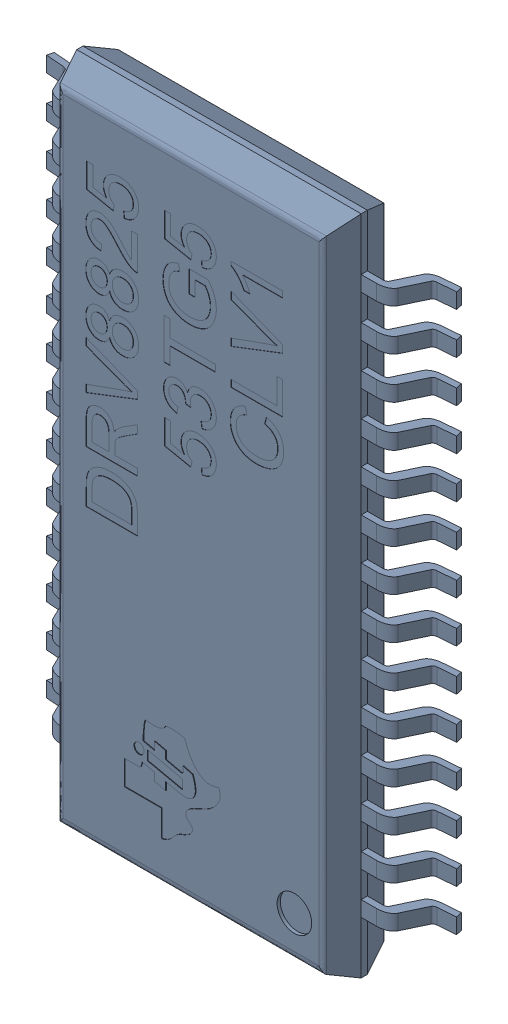
SolidWorks assembly DRV8825 Driver v9 (4), configuration Default. Lengths in mm.
Overall size (6.33 10.21 1.04).
2 component instances, 1 part files, 0 mates.
Components (placement in the parent):
- DRV8825 53TG5 CLV1 (4)-1: DRV8825 53TG5 CLV1 (4) [Default] at (6.5481 7.5317 9.8148) x (1 0 0) z (0 -1 0) size (6.33 1.04 10.21)
  - Package (4)-1: Package (4) [Default] at origin size (6.33 1.04 10.21)
